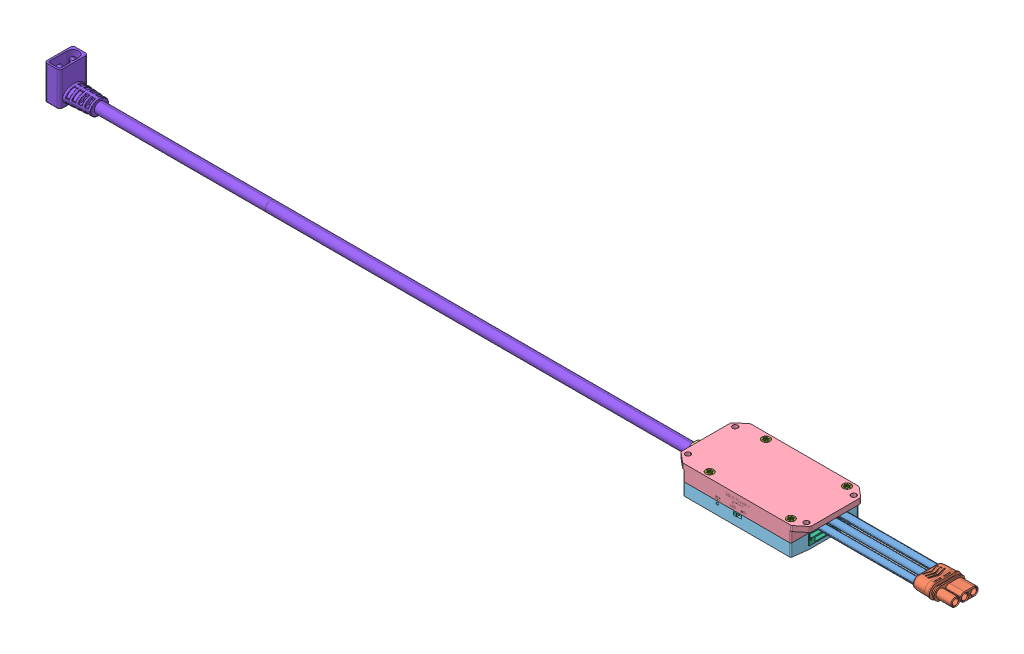
SolidWorks assembly C620无刷电机调速器, configuration Default. Lengths in mm.
Overall size (345.36 15.69 26.13).
15 component instances, 8 part files, 0 mates.
Components (placement in the parent):
- C620无刷电机调速器.STEP-1: C620无刷电机调速器.STEP [Default] at origin size (345.36 15.69 26.13)
  - 9.STEP-1: 9.STEP [Default] at (63.0501 2 0) x (0 0 1) z (1 0 0) size (12.31 5.31 60.01)
    - 14.STEP-1: 14.STEP [Default] at (4 0 -0.7) size (2.5 2.5 50)
    - 14.STEP-2: 14.STEP [Default] at (0 0 -0.7) x (0.422263 0.906473 0) z (0 0 1) size (2.5 2.5 50)
    - 14.STEP-3: 14.STEP [Default] at (-4 0 -0.7) size (2.5 2.5 50)
    - 1.STEP-1: 1.STEP [Default] at (-18.7519 0 2.7064) x (-1 0 0) z (0 0 1) size (12.31 5.31 14.5)
  - 6.STEP-1: 6.STEP [Default] at (-2.2 39.826 -7.4409) x (0 -0.431667 0.902033) z (-1 0 0) size (8.67 8.67 10.5)
  - 7.STEP-1: 7.STEP [Default] at (-1.7 0.6 0) size (49.4 6 25.8)
  - 8.STEP-1: 8.STEP [Default] at (-1.7 -0.6 0) x (0 -1 0) z (0 0 1) size (6.5 41 25.8)
  - 2.STEP-1: 2.STEP [Default] at (15.6004 -0.6014 9.8) x (0 0 -1) z (0 1 0) size (24.83 40.8 4.35)
  - 5.STEP-1: 5.STEP [Default] at (16.6 -3.6 -10.7) x (-0.36263 0 0.931933) z (-0.931933 0 -0.36263) size (3 9 3)
  - 5.STEP-2: 5.STEP [Default] at (16.6 -3.6 10.7) size (3 9 3)
  - 5.STEP-3: 5.STEP [Default] at (-14.3 -3.6 10.7) size (3 9 3)
  - 5.STEP-4: 5.STEP [Default] at (-14.3 -3.6 -10.7) size (3 9 3)
  - 10.STEP-1: 10.STEP [Default] at (-177.4931 0.4104 -3.9137) x (1 0 0) z (0 -1 0) size (250.81 10.82 13.76)
